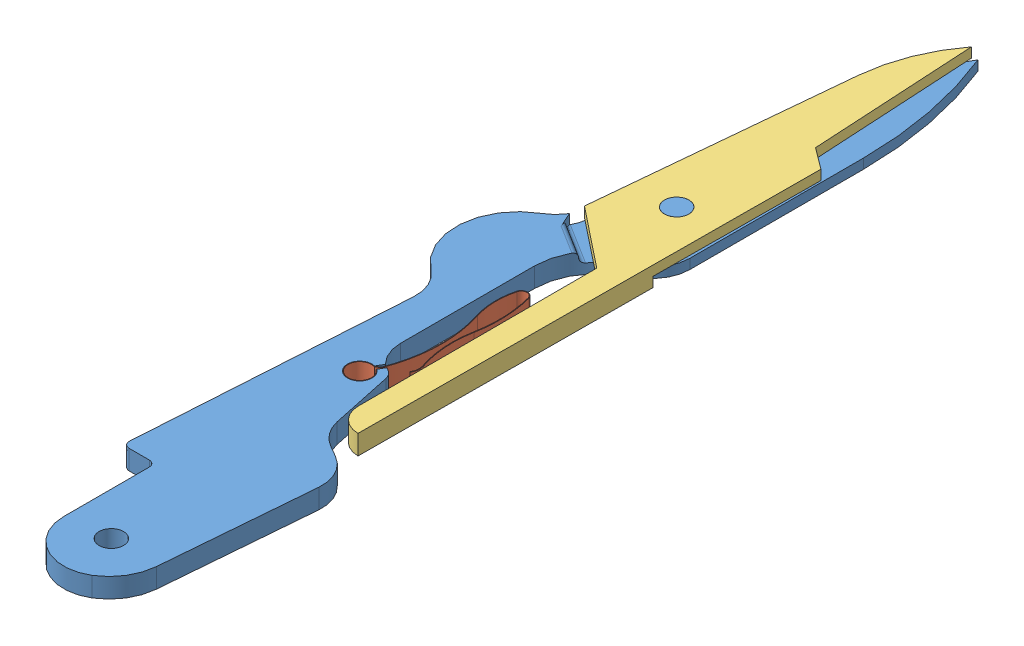
SolidWorks assembly scissors, configuration Default. Lengths in mm.
Overall size (17.57 1.82 80.78).
3 component instances, 3 part files, 5 mates.
Components (placement in the parent):
- scissors1-1: scissors1 [Default] at origin size (14.94 1.82 80.78)
- tensed_spring-1: tensed_spring [Default] at (15.3791 -0.8 -13.3543) x (0.992407 0 -0.123) z (0 1 0) size (4.32 13.19 1.6)
- scissor arm2-1: scissor arm2 [Default] at (15.5396 -0.8 -22.5845) x (0.985924 0 -0.167194) z (0.167194 0 0.985924) size (9 1.6 52)
Mates (geometry in assembly coordinates):
- Concentric3: concentric: cylinder of scissors1-1 through (4.8 -0.8 -25.9739) axis (0 1 0) radius 1; cylinder of tensed_spring-1 through (4.8 0.8 -25.9739) axis (0 -1 0) radius 1
- Concentric4: concentric: circle of scissors1-1; circle of scissor arm2-1
- LimitAngle1: limit planar angle = 0.056723 rad: line of scissors1-1 through (6.2991 0 -72.3751) axis (0 0 1); line of scissor arm2-1 through (6.8455 0 -73.8525) axis (0.056693 0 0.998392)
- Coincident4: coincident: plane of scissors1-1 through (0 0 0) normal (0 1 0); plane of scissor arm2-1 through (15.5396 0 -22.5845) normal (0 -1 0)
- Coincident5: coincident: plane of scissors1-1 through (3.6115 0.8 -40.1134) normal (0 1 0); plane of tensed_spring-1 through (5.2466 0.8 -27.0224) normal (0 1 0)
